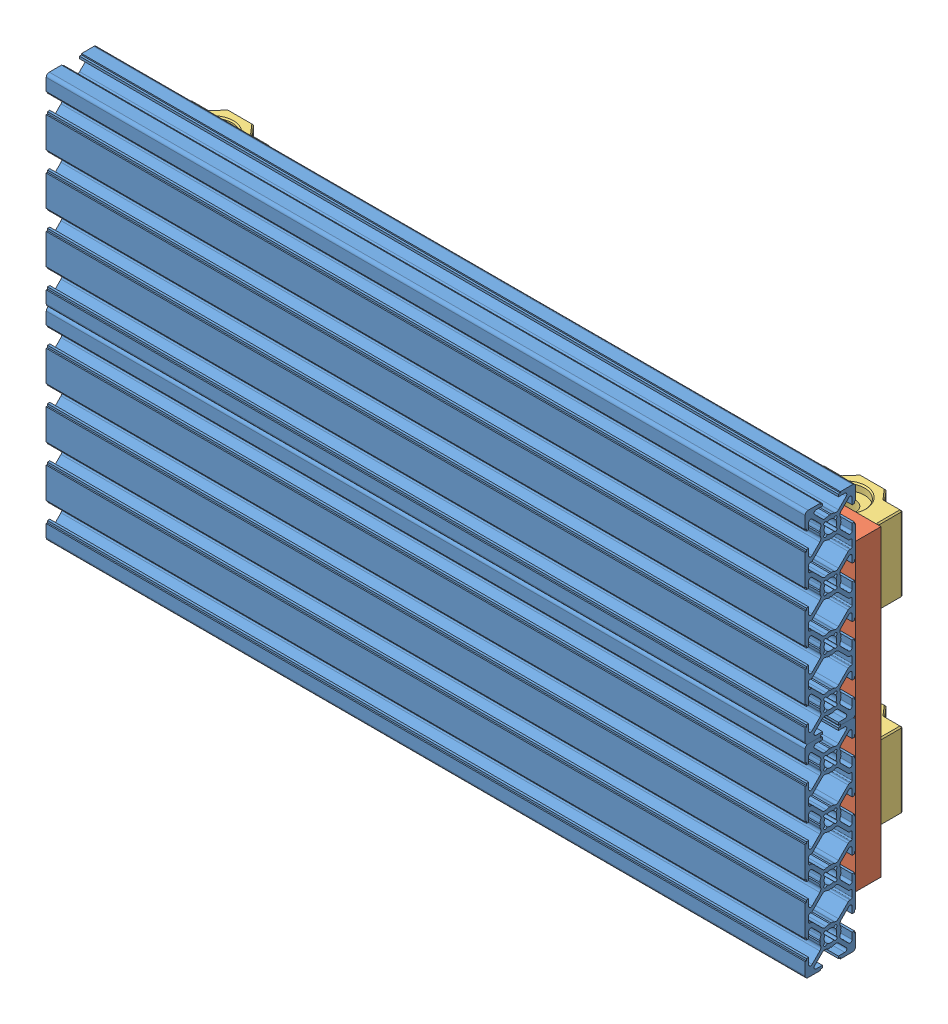
SolidWorks assembly AXIS_Y_DYNAMIC-but_bigger, configuration Default. Lengths in mm.
Overall size (300 160 52).
8 component instances, 3 part files, 12 mates.
Components (placement in the parent):
- 20x80x200_surface-1: 20x80x200_surface [Varsayılan] at (150 -70 0) x (0 1 0) z (1 0 0) size (80 20 300)
- 20x80x200_surface-2: 20x80x200_surface [Varsayılan] at (150 10 0) x (0 1 0) z (1 0 0) size (80 20 300)
- y_axis_elevation-1: y_axis_elevation [Default] at (125 0 -20) x (0 1 0) z (1 0 0) size (120 10 50)
- y_axis_elevation-3: y_axis_elevation [Default] at (-125 0 -20) x (0 1 0) z (1 0 0) size (120 10 50)
- linear_bearing_caged-5: linear_bearing_caged [Default] at (125 37 -31) x (1 0 0) z (0 1 0) size (34 22 30)
- linear_bearing_caged-6: linear_bearing_caged [Default] at (125 -37 -31) x (1 0 0) z (0 1 0) size (34 22 30)
- linear_bearing_caged-7: linear_bearing_caged [Default] at (-125 37 -31) x (1 0 0) z (0 1 0) size (34 22 30)
- linear_bearing_caged-8: linear_bearing_caged [Default] at (-125 -37 -31) x (1 0 0) z (0 1 0) size (34 22 30)
Mates (geometry in assembly coordinates):
- Coincident1: coincident anti-aligned: plane of 20x80x200_surface-1 through (-150 0 3.95) normal (0 1 0); plane of 20x80x200_surface-2 through (-150 0 8.8) normal (0 -1 0)
- Coincident2: coincident aligned: plane of 20x80x200_surface-1 through (-150 -13.95 10) normal (0 0 1); plane of 20x80x200_surface-2 through (-150 26.05 10) normal (0 0 1)
- Coincident3: coincident aligned: plane of 20x80x200_surface-1 through (150 -75.6787 -7.8) normal (1 0 0); plane of 20x80x200_surface-2 through (150 4.3213 -7.8) normal (1 0 0)
- Coincident4: coincident anti-aligned: plane of 20x80x200_surface-2 through (-150 53.95 -10) normal (0 0 -1); plane of y_axis_elevation-1 through (125 0 -10) normal (0 0 1)
- Coincident5: coincident aligned: plane of 20x80x200_surface-2 through (150 4.3213 -7.8) normal (1 0 0); plane of y_axis_elevation-1 through (150 60 -10) normal (1 0 0)
- Width1: width anti-aligned: plane of y_axis_elevation-1 through (150 60 -10) normal (0 1 0); plane of 20x80x200_surface-1 through (150 -60 -10) normal (0 -1 0); plane of y_axis_elevation-1 through (-150 -80 8.8) normal (0 -1 0); plane of 20x80x200_surface-2 through (-150 80 3.95) normal (0 1 0)
- Coincident6: coincident anti-aligned: plane of 20x80x200_surface-2 through (-150 53.95 -10) normal (0 0 -1); plane of y_axis_elevation-3 through (-125 0 -10) normal (0 0 1)
- Coincident7: coincident aligned: plane of 20x80x200_surface-2 through (-150 4.3213 -7.8) normal (-1 0 0); plane of y_axis_elevation-3 through (-150 60 -10) normal (-1 0 0)
- Coincident8: coincident aligned: plane of y_axis_elevation-1 through (150 60 -10) normal (0 1 0); plane of y_axis_elevation-3 through (-100 60 -10) normal (0 1 0)
- Coincident9: coincident anti-aligned: plane of y_axis_elevation-1 through (125 0 -20) normal (0 0 -1); plane of linear_bearing_caged-5 through (142 52 -20) normal (0 0 1)
- Concentric1: concentric anti-aligned: cylinder of y_axis_elevation-1 through (137 46 -20) axis (0 0 1) radius 1.5; cylinder of linear_bearing_caged-5 through (137 46 -15.7574) axis (0 0 -1) radius 1.5
- Concentric2: concentric anti-aligned: cylinder of y_axis_elevation-1 through (113 28 -20) axis (0 0 1) radius 1.5; cylinder of linear_bearing_caged-5 through (113 28 -15.7574) axis (0 0 -1) radius 1.5
